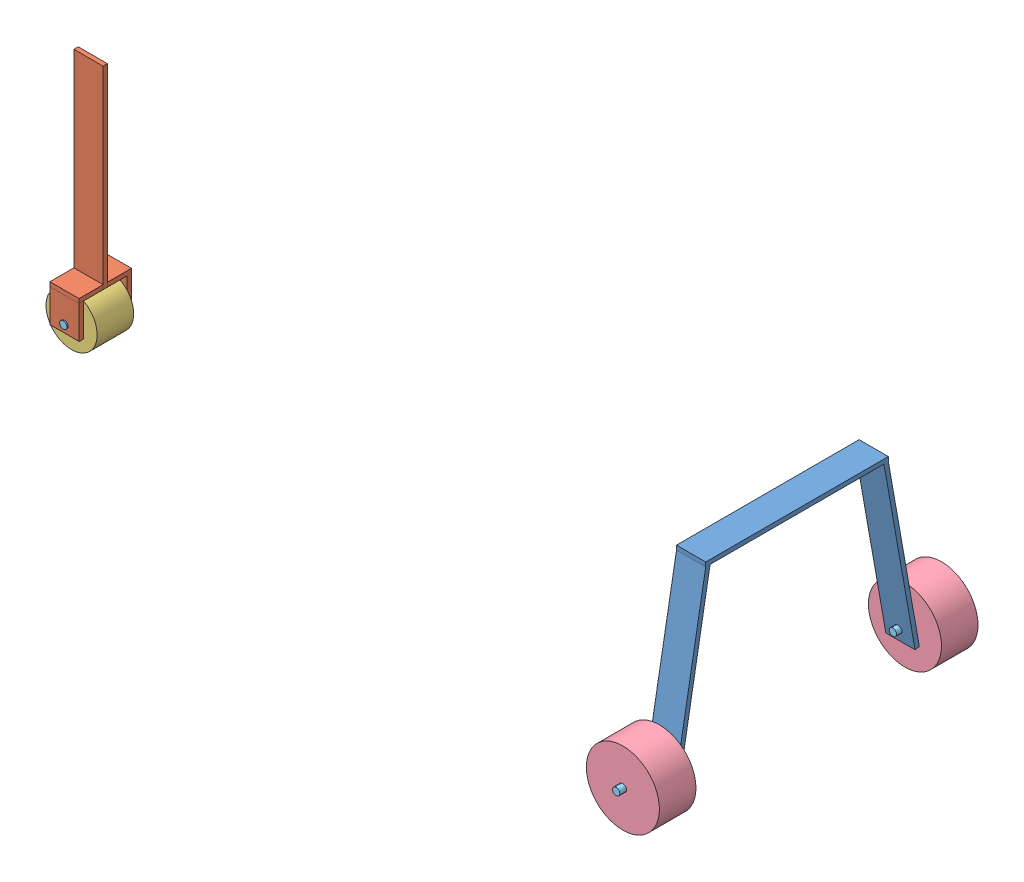
SolidWorks assembly landing assembly, configuration Default. Lengths in mm.
Overall size (525.77 169.96 230.4).
8 component instances, 5 part files, 0 mates.
Components (placement in the parent):
- land_main-1: land_main [Default] at (151.0823 136.9619 92.2339) size (20.32 125.68 170.08)
- land_nose-1: land_nose [Default] at (-329.8511 98.1721 89.1662) size (20.32 157.48 36.48)
- tire1.7-1: tire1.7 [Default] at (-331.5455 13.3021 78.5448) size (35.56 35.56 25.4)
- tire2.5-1: tire2.5 [Default] at (151.0425 22.5459 -18.4153) size (50.8 50.8 25.4)
- tire2.5-2: tire2.5 [Default] at (151.0327 22.3928 177.7331) size (50.8 50.8 25.4)
- land_rod-1: land_rod [Default] at (-331.629 13.1627 71.5107) size (5.08 5.08 38.1)
- land_rod-2: land_rod [Default] at (150.8894 22.5559 169.5709) size (5.08 5.08 38.1)
- land_rod-3: land_rod [Default] at (151.0166 22.4423 -22.7261) size (5.08 5.08 38.1)
